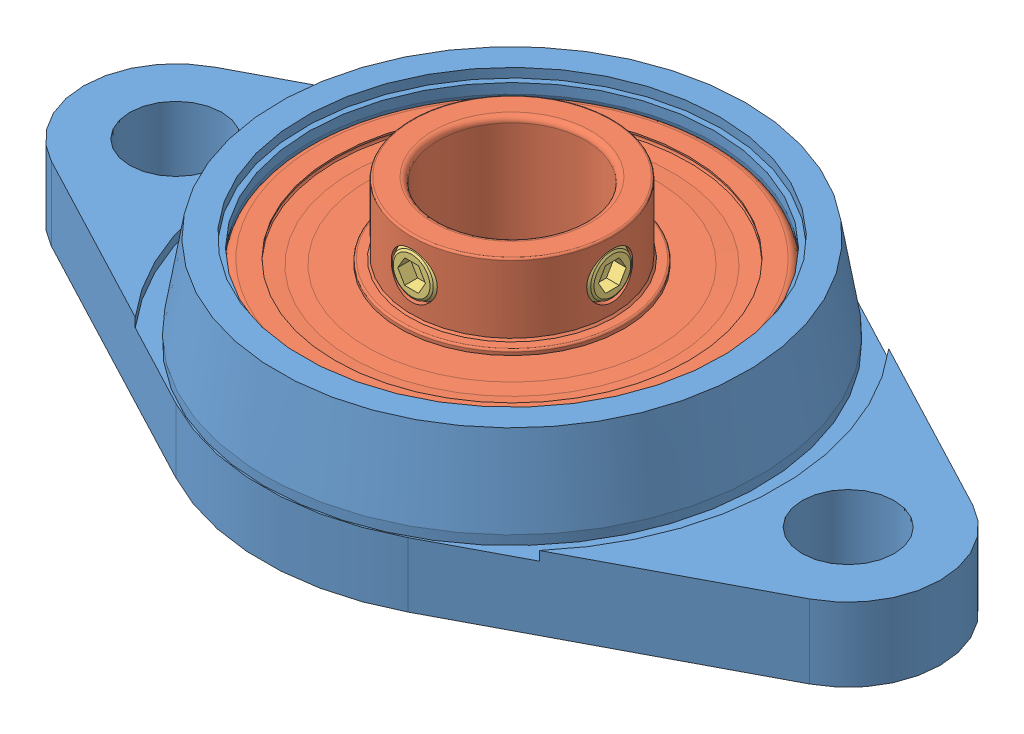
SolidWorks assembly KFL08, configuration Varsayılan. Lengths in mm.
Overall size (46.5 11.35 27).
4 component instances, 3 part files, 10 mates.
Components (placement in the parent):
- KFL08_Flange-1: KFL08_Flange [Default] at origin size (46.5 8.5 27)
- KFL08_608-RS-1: KFL08_608-RS [Default] at (0 4 0) x (1 0 0) z (0 -1 0) size (22.91 22.91 10.85)
- socket set screw cone point_am-1: socket set screw cone point_am [B18.3.6M - M2.5 x 0.45 x 2 Hex Socket Cone Pt. SS --S] at (0 9.425 5.45) x (0 0 -1) z (1 0 0) size (2 2.5 2.5)
- socket set screw cone point_am-2: socket set screw cone point_am [B18.3.6M - M2.5 x 0.45 x 2 Hex Socket Cone Pt. SS --S] at (5.45 9.425 0) x (-1 0 0) z (0 0 -1) size (2 2.5 2.5)
Mates (geometry in assembly coordinates):
- Coincident1: coincident aligned: plane of KFL08_Flange-1 through (0 0.5 0) normal (0 -1 0); plane of KFL08_608-RS-1 through (0 0.5 9.6) normal (0 -1 0)
- Coincident2: coordinate: point of KFL08_Flange-1; point of assembly
- Coincident3: coincident aligned: plane of KFL08_Flange-1 through (0 0 0) normal (1 0 0); plane of KFL08_608-RS-1
- Concentric2: concentric aligned: cylinder of KFL08_608-RS-1 through (0 9.425 5.45) axis (0 0 1) radius 1.25; cylinder of socket set screw cone point_am-1 through (0 9.425 18.15) axis (0 0 1) radius 1.25
- Tangent1: tangent aligned: cylinder of KFL08_608-RS-1 through (0 0.5 0) axis (0 -1 0) radius 5.45; plane of socket set screw cone point_am-1 through (0 9.425 5.45) normal (0 0 1)
- Concentric3: concentric aligned: cylinder of KFL08_608-RS-1 through (5.45 9.425 0) axis (1 0 0) radius 1.25; cylinder of socket set screw cone point_am-2 through (18.15 9.425 0) axis (1 0 0) radius 1.25
- Tangent3: tangent aligned: cylinder of KFL08_608-RS-1 through (0 0.5 0) axis (0 -1 0) radius 5.45; plane of socket set screw cone point_am-2 through (5.45 9.425 0) normal (1 0 0)
- Parallel1: parallel aligned: plane of socket set screw cone point_am-1; plane of assembly through (0 0 0) normal (0 1 0)
- Parallel2: parallel aligned: plane of socket set screw cone point_am-2; plane of assembly through (0 0 0) normal (0 1 0)
- Coincident4: coincident anti-aligned: line of KFL08_Flange-1 through (9.35 0 -0.425) axis (0 0 1); line of KFL08_608-RS-1 through (10.25 0 11.05) axis (0 0 -1)
